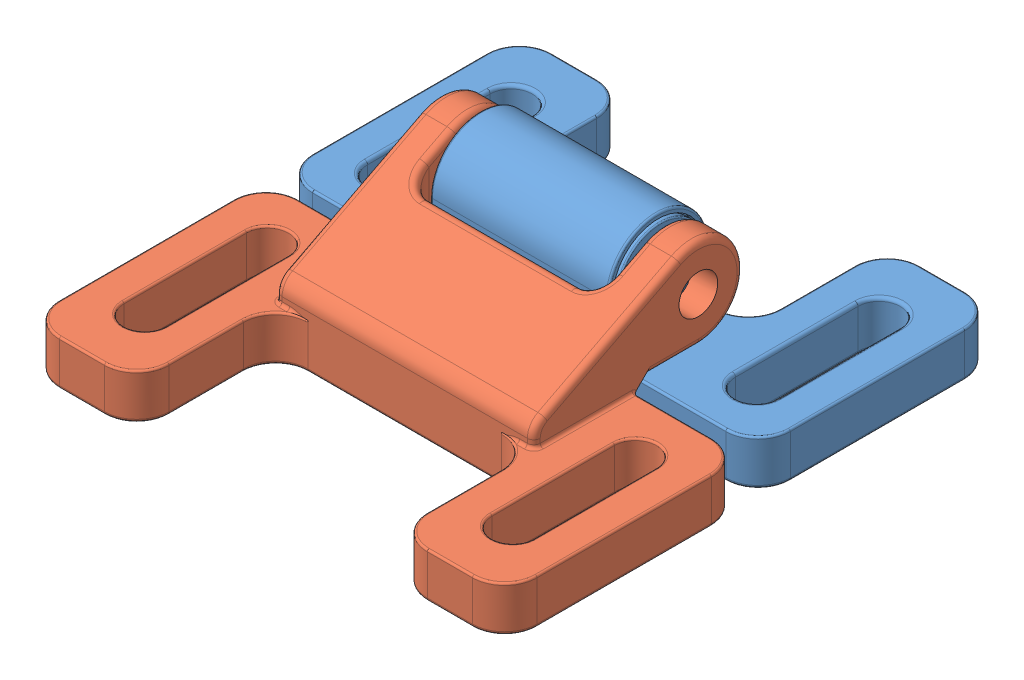
SolidWorks assembly 355.0700A.01.STEP, configuration По умолчанию. Lengths in mm.
Overall size (74 23 76.25).
2 component instances, 2 part files, 0 mates.
Components (placement in the parent):
- 355-0700a-01-1: 355-0700a-01 [По умолчанию] at (-8.0798 -9.9953 94.751) size (74 23 37)
- 355-0701B-01-1: 355-0701B-01 [По умолчанию] at (-8.0798 -9.9953 94.751) size (74 22.25 54.01)
